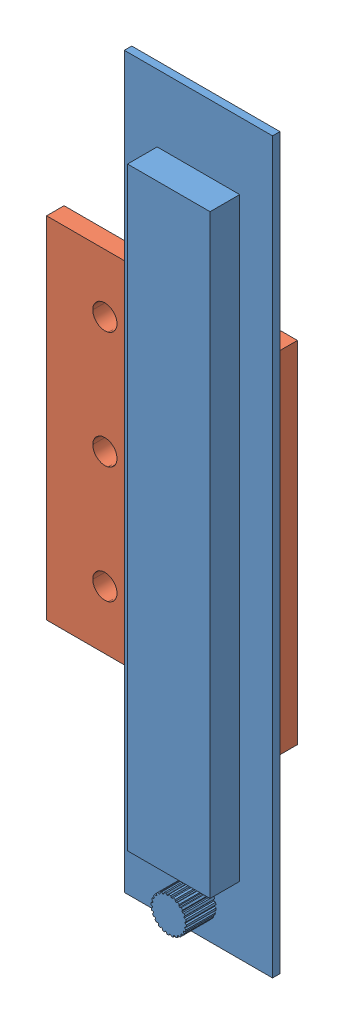
SolidWorks assembly Matheson Trigas Plated, configuration Default. Lengths in mm.
Overall size (80 250 18.7).
2 component instances, 2 part files, 3 mates.
Components (placement in the parent):
- Matheson_Tri_Gas-1: Matheson_Tri_Gas [Default] at (111.3103 133.6146 173.9116) size (50.8 250 12.7)
- 40_4366-1: 40_4366 [Default] at (96.7103 73.6146 167.9116) size (80 120 6)
Mates (geometry in assembly coordinates):
- Coincident1: coincident: plane of Matheson_Tri_Gas-1 through (111.3103 133.6146 173.9116) normal (0 0 -1); plane of 40_4366-1 through (125.9103 73.6146 173.9116) normal (0 0 1)
- Distance1: distance = 65 mm: plane of 40_4366-1 through (136.7103 193.6146 173.9116) normal (0 1 0); line of Matheson_Tri_Gas-1 through (136.7103 258.6146 173.9116) axis (-1 0 0)
- Coincident4: coincident aligned: plane of Matheson_Tri_Gas-1 through (136.7103 8.6146 176.4516) normal (1 0 0); plane of 40_4366-1 through (136.7103 73.6146 173.9116) normal (1 0 0)
